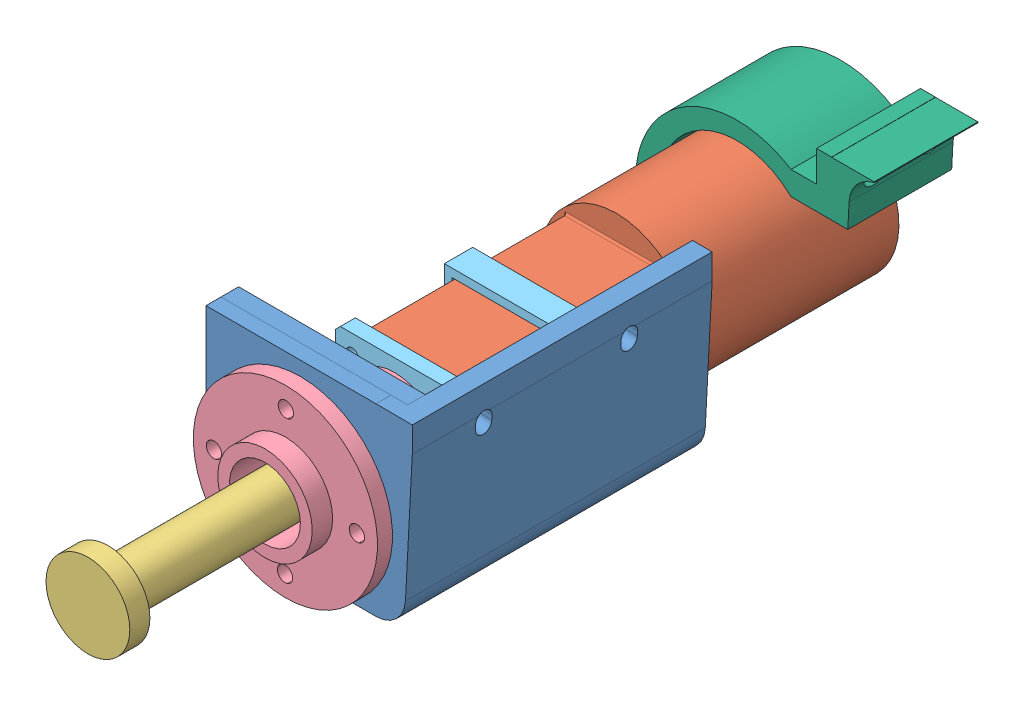
SolidWorks assembly D-01-00, configuration Default. Lengths in mm.
Overall size (163.91 86.22 319).
8 component instances, 7 part files, 10 mates.
Components (placement in the parent):
- S-01-01-01-1: S-01-01-01 [Default] at (62.5689 370.838 601.9542) size (658.2 105 450) (hidden)
- D-01-02-1: D-01-02 [Default] at (-188.5719 315.838 834.4542) x (0 0 -1) z (1 0 0) size (205.75 78 138.28)
- D-01-04-1: D-01-04 [Default] at (-199.7546 211.4142 769.8925) x (0 0 1) z (0 1 0) size (311.5 78.45 78.45)
  - moteur_pla_simplifie-2: moteur_pla_simplifie [Default] at (-156.9384 51.1827 137.4238) size (176.5 64 64)
  - moteur_axe_pla_simplifie-1: moteur_axe_pla_simplifie [Default] at (3.5616 51.1827 137.4238) size (151 35.5 35.5)
  - front_housing_moteur_pla_simplifie-2: front_housing_moteur_pla_simplifie [Default] at (64.5616 51.1827 137.4238) x (1 0 0) z (0 0.00581 0.999983) size (60 78 78)
- D-01-03-1: D-01-03 [Default] at (-173.6321 327.188 794.4741) x (-0.000012 0 -1) z (0 -1 0) size (78.5 77.86 66.5)
- D-01-01-1: D-01-01 [Default] at (-148.5686 348.838 605.4542) x (-1 0 0) z (0 0 -1) size (123.62 80 44)
Mates (geometry in assembly coordinates):
- Coincident1: coincident anti-aligned: plane of Plancher simple-1 through (-104.0891 327.6838 376.9542) normal (-0.99863 0.052336 0); plane of braquette_bleue_46.2_SLDPRT-1 through (-101.1877 383.0446 748.6015) normal (0.99863 -0.052336 0)
- Coincident2: coincident anti-aligned: plane of Plancher simple-1 through (-266.5311 315.838 376.9542) normal (0 1 0); plane of braquette_bleue_46.2_SLDPRT-1 through (-108.5719 315.838 834.4542) normal (0 -1 0)
- Concentric1: concentric aligned: circle of braquette bleu-1; circle of assemblage_moteur_pla_simplifie-1/front_housing_moteur_pla_simplifie-2
- Parallel2: parallel anti-aligned: plane of braquette_bleue_46.2_SLDPRT-1 through (-108.5719 322.188 667.4542) normal (0 1 0); plane of assemblage_moteur_pla_simplifie-1/moteur_pla_simplifie-2 through (-127.5719 327.838 789.4542) normal (0 -1 0)
- Coincident9: coincident anti-aligned: plane of braquette_bleue_46.2_SLDPRT-1 through (-108.5719 322.188 667.4542) normal (0 1 0); plane of braquette gearbox_46.2-1 through (-173.6321 322.188 794.4741) normal (0 -1 0)
- Coincident19: coincident anti-aligned: plane of braquette_bleue_46.2_SLDPRT-1 through (-108.5719 315.838 834.4542) normal (0 0 1); plane of assemblage_moteur_pla_simplifie-1/front_housing_moteur_pla_simplifie-2 through (-148.5719 348.838 834.4542) normal (0 0 -1)
- Concentric22: concentric aligned: cylinder of assemblage_moteur_pla_simplifie-1/moteur_pla_simplifie-2 through (-148.5719 348.838 700.6742) axis (0 0 -1) radius 32; cylinder of braquette moteur- v2-1 through (-148.5719 348.838 649.4542) axis (0 0 -1) radius 33
- Distance1: distance = 7.5 mm anti-aligned: plane of assemblage_moteur_pla_simplifie-1/front_housing_moteur_pla_simplifie-2 through (-148.5719 348.838 834.4542) normal (0 0 -1); plane of Plancher simple-1 through (-116.5719 328.338 826.9542) normal (0 0 1)
- Coincident20: coincident anti-aligned: plane of Plancher simple-1 through (-266.5311 315.838 376.9542) normal (0 1 0); plane of D-01-01-1 through (-181.5719 315.838 649.4542) normal (0 -1 0)
- Distance2: distance = 7.5 mm aligned: plane of braquette moteur- v2-1 through (-148.699 346.4685 605.4542) normal (0 0 -1); plane of assemblage_moteur_pla_simplifie-1/moteur_pla_simplifie-2 through (-148.5719 348.838 612.9542) normal (0 0 -1)
